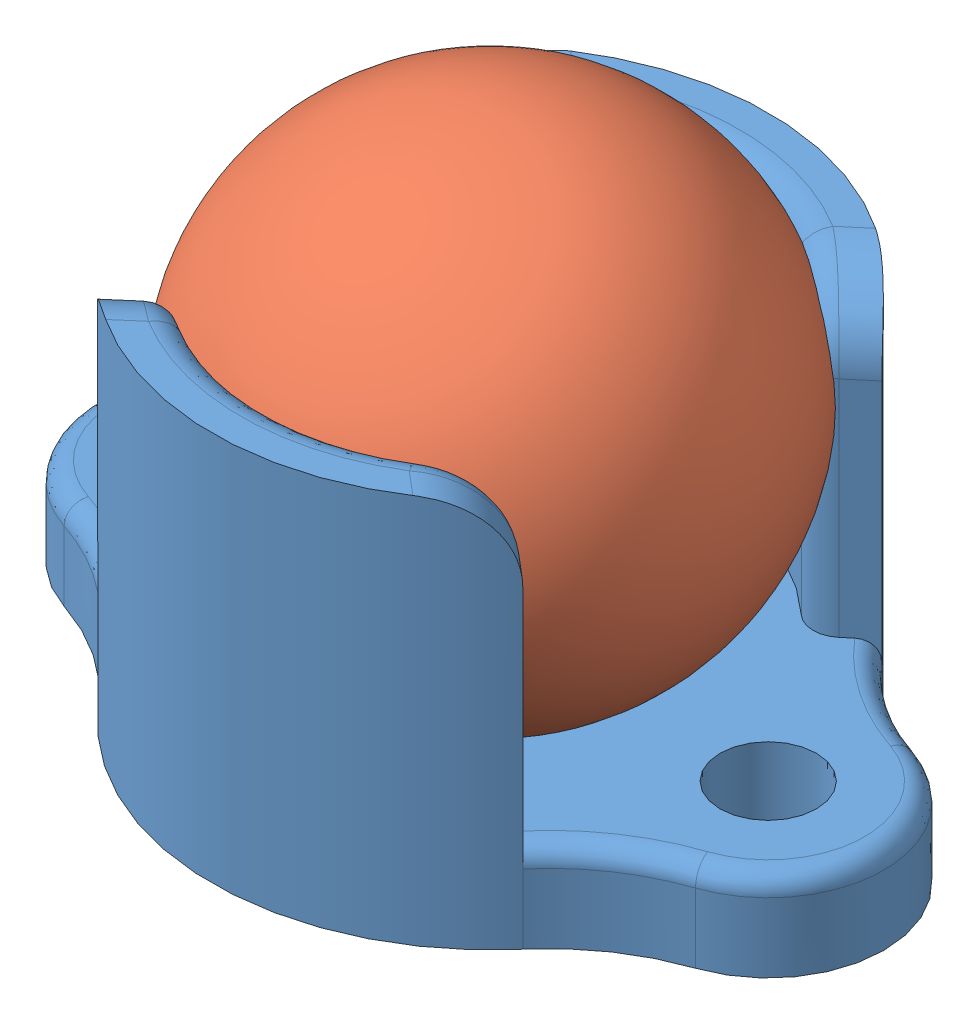
SolidWorks assembly Caster Assembly, configuration Default. Lengths in mm.
Overall size (20.45 13.77 14.75).
2 component instances, 2 part files, 2 mates.
Components (placement in the parent):
- Caster Holder-1: Caster Holder [Default] at (5.4803 7.1159 15.7911) size (20.45 10.22 14.4)
- Caster Ball-1: Caster Ball [Default] at (5.4803 14.5403 15.7911) x (0.984131 0 0.177443) z (0 -1 0) size (12.7 12.7 12.7)
Mates (geometry in assembly coordinates):
- Tangent1: tangent: circle of Caster Holder-1; sphere of Caster Ball-1
- Coincident1: coincident anti-aligned: axis of Caster Holder-1 through (5.4803 17.2159 15.7911) axis (0 -1 0); axis of Caster Ball-1 through (5.4803 10.1409 15.7911) axis (0 1 0)
